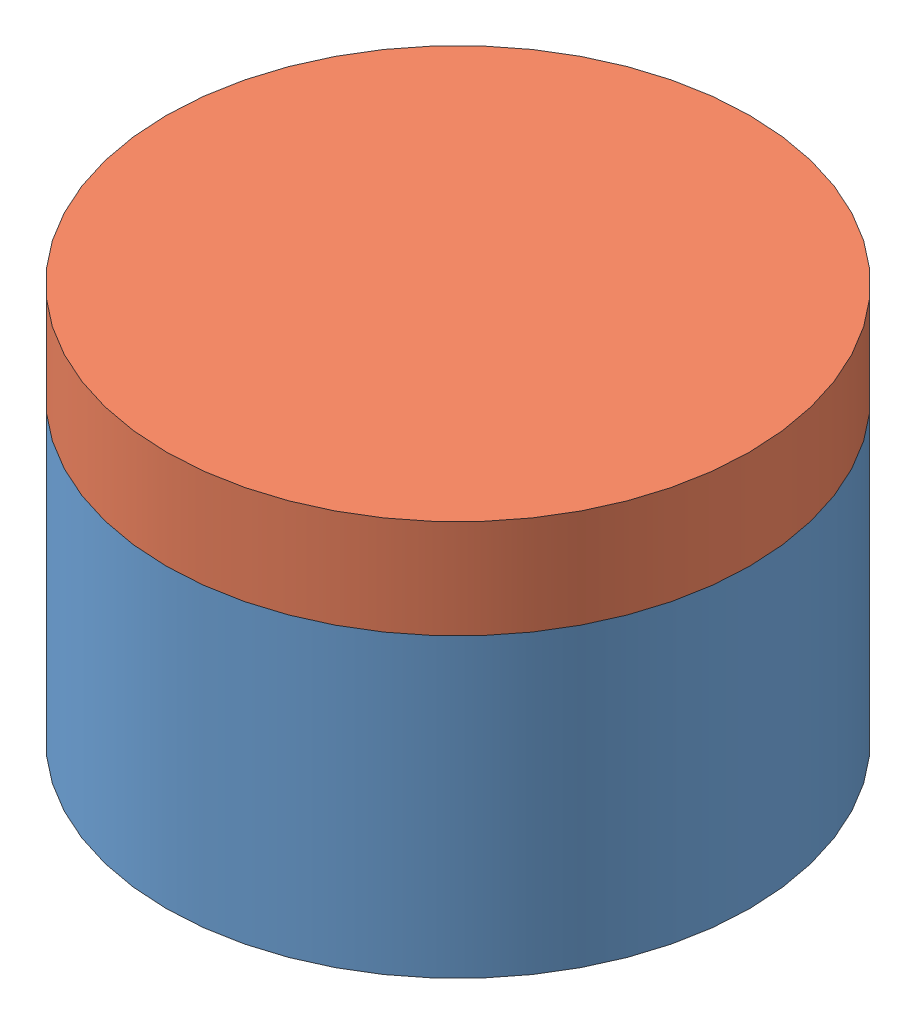
SolidWorks assembly cylinder, configuration Default. Lengths in mm.
Overall size (74.99 50.8 75.86).
2 component instances, 2 part files, 1 mates.
Components (placement in the parent):
- cylinder_bottom-1: cylinder_bottom [Default] at origin size (74.93 38.95 75.86)
- cylinder_top-1: cylinder_top [Default] at (0 50.8 0) x (-1 0 0) z (0 0 1) size (74.99 38.12 75.86)
Mates (geometry in assembly coordinates):
- Concentric2: concentric anti-aligned: circle of cylinder_bottom-1; circle of cylinder_top-1
